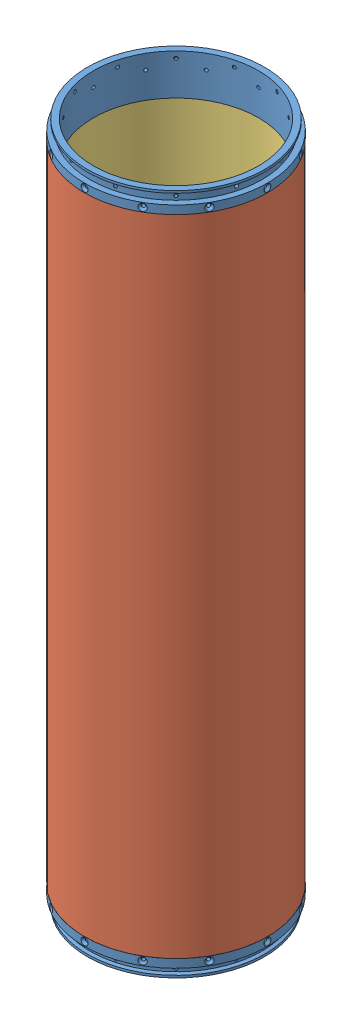
SolidWorks assembly module24, configuration Default. Lengths in mm.
Overall size (202.16 629.76 202.16).
6 component instances, 4 part files, 7 mates.
Components (placement in the parent):
- moduleRing-1: moduleRing [Default] at (25.7042 -360.5051 -16.6209) size (168.91 37.68 168.91)
- moduleRing-2: moduleRing [Default] at (25.7042 248.3364 -16.6209) x (-1 0 0) z (0 0 1) size (168.91 37.68 168.91)
- compositeOuterSleeve-1: compositeOuterSleeve [Default] at (25.7042 -353.5986 -16.6209) x (0.221764 0 0.9751) z (-0.9751 0 0.221764) size (168.91 595.03 168.91)
- compositeInnerSleeve-1: compositeInnerSleeve [Default] at (25.7042 -343.4386 -16.6209) x (0.952124 0 0.305713) z (-0.305713 0 0.952124) size (154.43 574.71 154.43)
- moduleRing_female-1: moduleRing_female [Default] at (-230.5189 -285.4213 70.9885) (suppressed, hidden)
- moduleRing_female-2: moduleRing_female [Default] at (-230.5189 328.4441 70.9885) x (-0.866025 0 -0.5) z (-0.5 0 0.866025) (suppressed, hidden)
Mates (geometry in assembly coordinates):
- Concentric1: concentric anti-aligned: cylinder of moduleRing-1 through (25.7042 -325.6216 -16.6209) axis (0 1 0) radius 76.708; cylinder of compositeInnerSleeve-1 through (25.7042 231.2699 -16.6209) axis (0 -1 0) radius 76.708
- Coincident1: coincident anti-aligned: plane of moduleRing-1 through (109.1432 -343.4386 -16.6209) normal (0 1 0); plane of compositeInnerSleeve-1 through (25.7042 -343.4386 -16.6209) normal (0 -1 0)
- Concentric2: concentric anti-aligned: cylinder of moduleRing-1 through (25.7042 -325.6216 -16.6209) axis (0 1 0) radius 83.439; cylinder of compositeOuterSleeve-1 through (25.7042 241.431 -16.6209) axis (0 -1 0) radius 83.439
- Coincident2: coincident anti-aligned: plane of moduleRing-1 through (109.1432 -353.5986 -16.6209) normal (0 1 0); plane of compositeOuterSleeve-1 through (25.7042 -353.5986 -16.6209) normal (0 -1 0)
- Coincident3: coincident anti-aligned: plane of moduleRing-2 through (-57.7348 231.2699 -16.6209) normal (0 -1 0); plane of compositeInnerSleeve-1 through (25.7042 231.2699 -16.6209) normal (0 1 0)
- Concentric3: concentric aligned: cylinder of moduleRing-2 through (25.7042 213.453 -16.6209) axis (0 -1 0) radius 76.708; cylinder of compositeInnerSleeve-1 through (25.7042 231.2699 -16.6209) axis (0 -1 0) radius 76.708
- Parallel1: parallel aligned: cylinder of moduleRing-1 through (25.7042 -357.4796 67.8341) axis (0 0 1) radius 1.4732; cylinder of moduleRing-2 through (25.7042 245.3109 67.8341) axis (0 0 1) radius 1.4732
